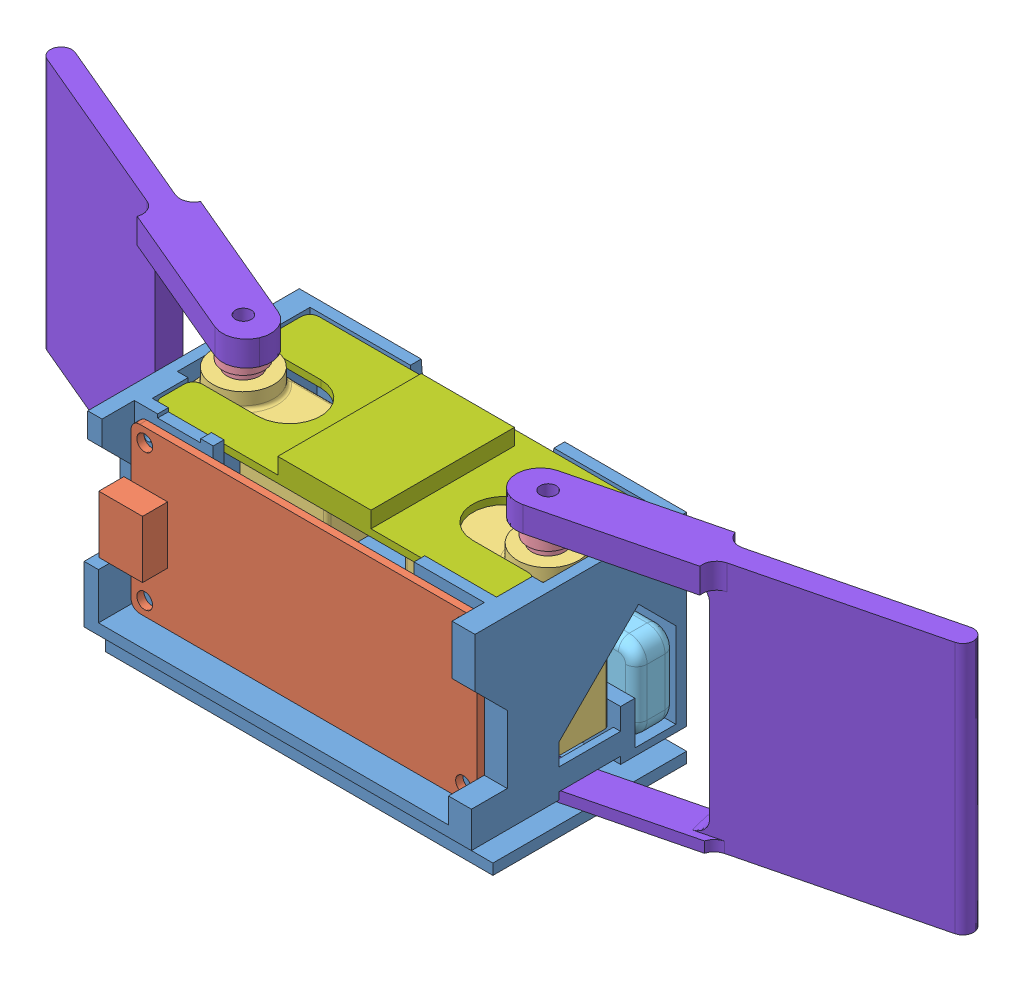
SolidWorks assembly Smarticle_Assembly, configuration Default. Lengths in mm.
Overall size (137.75 36.86 38.72).
16 component instances, 9 part files, 33 mates.
Components (placement in the parent):
- Body2-1: Body2 [Default] at (-7.5576 25.0818 58.1791) size (54 30.36 30)
- Feather-2: Feather [Default] at (-5.0176 53.9418 57.1791) x (1 0 0) z (0 1 0) size (49.26 4.5 22.86)
- Servo - Assembly-4: Servo - Assembly [Default] at (103.6002 37.1798 13.4482) size (29.38 26.5 10.29) (flexible)
  - Servo - Body-1: Servo - Body [Default] at (-78.8577 -3.7379 27.0308) size (20.3 22.2 8.7)
  - Servo - Horn-1: Servo - Horn [Default] at (-62.9077 22.0121 31.2808) x (0.97076 0 -0.240051) z (0.240051 0 0.97076) size (16 6.5 5.75)
- Servo - Assembly-5: Servo - Assembly [Default] at (-64.7153 37.1798 76.0099) x (-1 0 0) z (0 0 -1) size (29.16 26.5 12.1) (flexible)
  - Servo - Body-1: Servo - Body [Default] at (-78.8577 -3.7379 27.0308) size (20.3 22.2 8.7)
  - Servo - Horn-1: Servo - Horn [Default] at (-62.9077 22.0121 31.2808) x (0.921224 0 0.389031) z (-0.389031 0 0.921224) size (16 6.5 5.75)
- TopBoard-3: TopBoard [Default] at (43.4424 53.9418 32.6791) x (-1 0 0) z (0 0 -1) size (48 3.25 22) (hidden)
- Battery - Assembly-2: Battery - Assembly [Default] at (-9.331 41.8342 18.9221) x (-1 0 0) z (0 0 1) size (46.75 12.5 5.5)
  - Battery - Body-1: Battery - Body [Default] at (-55.7734 -0.4976 13.7569) size (36.5 11.75 5.5)
  - Battery - Connector-1: Battery - Connector [Default] at (-19.2734 -0.8726 13.7569) size (10.25 12.5 5.4)
- Servo - Solar Arm-1: Servo - Solar Arm [Default] at (37.3115 61.9418 45.2324) x (-0.133971 0 -0.990985) z (0 -1 0) size (63.7 6.75 36.7) (hidden)
- TopBoard-4: TopBoard [Default] at (43.4424 53.9418 32.6791) x (-1 0 0) z (0 0 -1) size (48 3.25 22)
- Arm2-3: Arm2 [Default] at (40.6424 26.7418 44.6791) x (0.97076 0 -0.240051) z (0 1 0) size (53.55 6.75 36.7)
- Arm2-4: Arm2 [Default] at (-1.8076 26.7418 44.7291) x (-0.921224 0 -0.389031) z (0 1 0) size (53.55 6.75 36.7)
Mates (geometry in assembly coordinates):
- Coincident1: coincident: plane of Body2-1 through (-7.5576 36.5818 56.1791) normal (0 0 1); plane of Feather-2 through (-5.0176 53.9418 56.1791) normal (0 0 -1)
- Coincident2: coincident: plane of Body2-1 through (-7.5576 31.0818 61.1791) normal (0 1 0); plane of Feather-2 through (-5.0176 31.0818 56.1791) normal (0 -1 0)
- Coincident3: coincident: plane of Body2-1 through (43.2424 25.0818 73.0485) normal (-1 0 0); plane of Feather-2 through (43.2424 53.9418 56.1791) normal (1 0 0)
- Coincident4: coincident: plane of Body2-1 through (-7.5576 33.4418 58.1791) normal (0 1 0); plane of Servo - Assembly-4/Servo - Body-1 through (24.7424 33.4418 48.9791) normal (0 -1 0)
- Coincident5: coincident: plane of Body2-1 through (-7.5576 36.5818 48.9791) normal (0 0 -1); plane of Servo - Assembly-4/Servo - Body-1 through (24.7424 33.4418 48.9791) normal (0 0 1)
- Coincident6: coincident: plane of Body2-1 through (44.9424 25.0818 58.1791) normal (-1 0 0); plane of Servo - Assembly-4/Servo - Body-1 through (44.9424 33.4418 48.9791) normal (1 0 0)
- Coincident9: coincident: plane of Body2-1 through (-7.5576 36.5818 48.9791) normal (0 0 -1); plane of Servo - Assembly-5/Servo - Body-1 through (14.1424 33.4418 48.9791) normal (0 0 1)
- Coincident10: coincident: plane of Body2-1 through (-7.5576 33.4418 58.1791) normal (0 1 0); plane of Servo - Assembly-5/Servo - Body-1 through (14.1424 33.4418 40.4791) normal (0 -1 0)
- Coincident11: coincident: plane of Body2-1 through (-6.0576 25.0818 58.1791) normal (1 0 0); plane of Servo - Assembly-5/Servo - Body-1 through (-6.0576 33.4418 40.4791) normal (-1 0 0)
- Coincident12: coincident: plane of Body2-1 through (46.4424 135.3227 54.6791) normal (0 0 -1); plane of TopBoard-3 through (43.4424 54.9418 54.6791) normal (0 0 1)
- Coincident13: coincident: plane of Body2-1 through (-7.5576 53.9418 58.1791) normal (0 1 0); plane of TopBoard-3 through (34.4424 53.9418 44.5791) normal (0 -1 0)
- Coincident14: coincident: plane of Body2-1 through (43.4424 46.1772 32.6791) normal (-1 0 0); plane of TopBoard-3 through (43.4424 54.9418 32.6791) normal (1 0 0)
- Coincident15: coincident: plane of Body2-1 through (-7.5576 109.4627 32.6791) normal (0 0 1); plane of Battery - Assembly-2/Battery - Body-1 through (46.4424 42.3318 32.6791) normal (0 0 -1)
- Coincident16: coincident: plane of Body2-1 through (-7.5576 30.5818 58.1791) normal (0 1 0); plane of Battery - Assembly-2/Battery - Body-1 through (46.4424 30.5818 38.1791) normal (0 -1 0)
- Concentric1: concentric: cylinder of Body2-1 through (40.6424 26.5818 44.6791) axis (0 -1 0) radius 2.25; circle of Servo - Solar Arm-1
- Coincident18: coincident: plane of Servo - Assembly-4/Servo - Horn-1 through (40.6924 59.9418 44.7291) normal (0 1 0); plane of Servo - Solar Arm-1 through (37.3115 59.9418 45.2324) normal (0 -1 0)
- Coincident20: coincident: plane of Body2-1 through (46.4424 36.5818 58.1791) normal (1 0 0); plane of Battery - Assembly-2/Battery - Body-1 through (46.4424 42.3318 38.1791) normal (1 0 0)
- Coincident22: coincident: plane of Body2-1 through (-7.5576 53.9418 58.1791) normal (0 1 0); plane of TopBoard-4 through (34.4424 53.9418 44.5791) normal (0 -1 0)
- Coincident26: coincident: plane of Body2-1 through (43.4424 46.1772 49.6791) normal (-1 0 0); plane of TopBoard-4 through (43.4424 54.9418 48.9791) normal (1 0 0)
- Coincident27: coincident: plane of Body2-1 through (46.4424 135.3227 54.6791) normal (0 0 -1); plane of TopBoard-4 through (43.4424 54.9418 54.6791) normal (0 0 1)
- Concentric2: concentric: circle of Body2-1; circle of ?
- Coincident28: coincident: plane of ? through (-1.8076 59.9418 44.7291) normal (0 1 0); plane of ? through (-2.3506 59.9418 48.0031) normal (0 -1 0)
- Parallel1: parallel: plane of ?; plane of ? through (-1.4496 -3.159 43.211) normal (0.205332 0 -0.978692)
- Concentric3: concentric: circle of Body2-1; circle of ?
- Coincident30: coincident: plane of Servo - Assembly-4/Servo - Horn-1 through (40.6924 59.9418 44.7291) normal (0 1 0); plane of ? through (39.7331 59.9418 41.4272) normal (0 -1 0)
- Parallel2: parallel: plane of Servo - Assembly-4/Servo - Horn-1 through (40.3143 59.9418 43.2001) normal (-0.240051 0 -0.97076); plane of ? through (41.0025 -3.159 46.1352) normal (0.240051 0 0.97076)
- Coincident32: coincident: plane of Servo - Assembly-5/Servo - Horn-1 through (-1.8076 59.9418 44.7291) normal (0 1 0); plane of Arm2-4 through (-1.8076 59.9418 44.7291) normal (0 -1 0)
- Concentric4: concentric: circle of Servo - Assembly-5/Servo - Horn-1; circle of Arm2-4
- Parallel3: parallel: plane of Servo - Assembly-5/Servo - Horn-1 through (-2.4203 59.9418 46.18) normal (-0.389031 0 0.921224); plane of Arm2-4 through (-3.1206 61.9418 47.8382) normal (-0.389031 0 0.921224)
- Concentric5: concentric: circle of Body2-1; circle of Arm2-3
- Coincident33: coincident: plane of Servo - Assembly-4/Servo - Horn-1 through (40.6924 59.9418 44.7291) normal (0 1 0); plane of Arm2-3 through (40.6424 59.9418 44.6791) normal (0 -1 0)
- Parallel4: parallel: plane of Servo - Assembly-4/Servo - Horn-1 through (41.0705 59.9418 46.258) normal (0.240051 0 0.97076); plane of Arm2-3 through (41.4526 61.9418 47.9554) normal (0.240051 0 0.97076)
- Coincident34: coincident: plane of Body2-1 through (-7.5576 33.4418 58.1791) normal (0 1 0); plane of Servo - Assembly-4/Servo - Body-1 through (24.7424 33.4418 48.9791) normal (0 -1 0)
